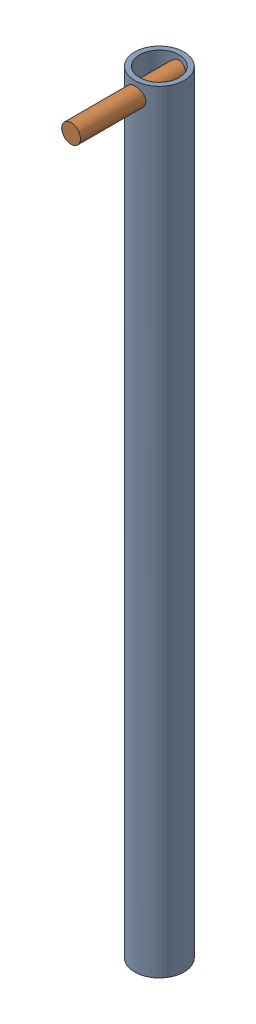
SolidWorks assembly FE-00003_ASM, configuration Default. Lengths in mm.
Overall size (33.34 520.7 76.2).
2 component instances, 2 part files, 0 mates.
Components (placement in the parent):
- FE-00003-1: FE-00003 [Default] at origin size (33.34 520.7 33.34)
- FE-00003-01-1: FE-00003-01 [Default] at (0 250.825 -16.6687) size (12.7 12.7 76.2)
